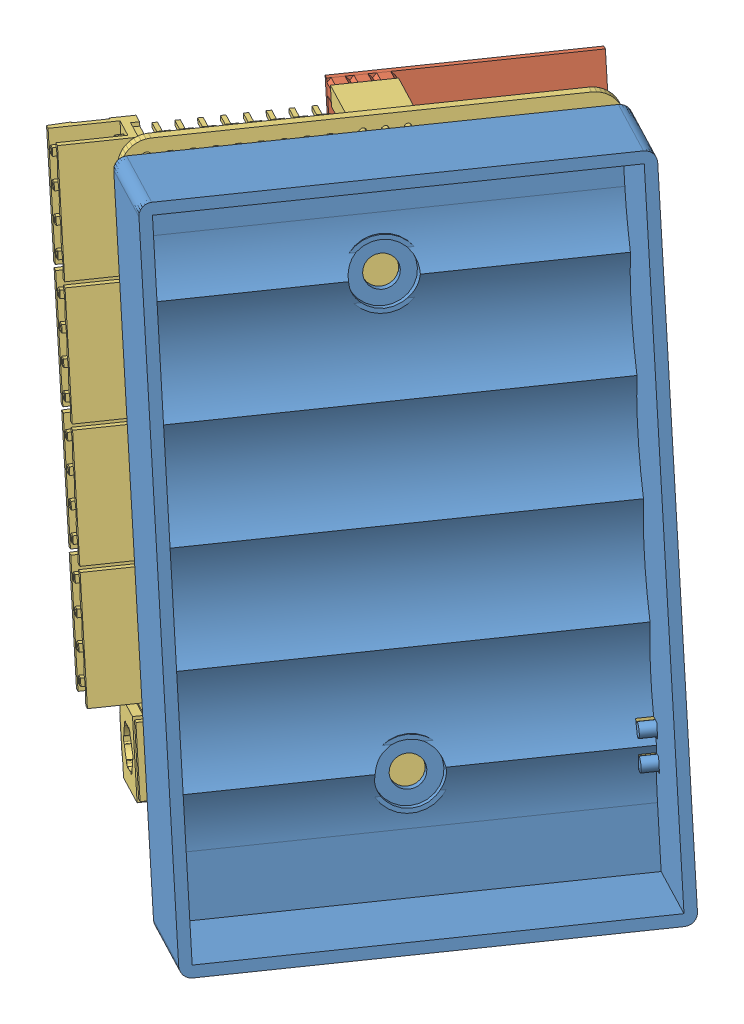
SolidWorks assembly Boitier_Electronique, configuration Défaut. Lengths in mm.
Overall size (84.35 91.62 83.87).
3 component instances, 3 part files, 7 mates.
Components (placement in the parent):
- Coupleur6PilesAA-1: Coupleur6PilesAA [Défaut] at (28.5112 -11.4596 149.0979) x (0.569655 -0.000137 -0.821884) z (-0.230919 0.959692 -0.160212) size (59.2 16.1 90)
- Bluetooth Module For mBot V1.0-1: Bluetooth Module For mBot V1.0 [Défaut] at (-5.2612 11.173 119.3562) x (-0.569622 0 0.821907) z (-0.788777 -0.281054 -0.546662) size (31 20.32 11.44)
- MegaPi-1: MegaPi [Défaut] at (4.2784 -56.3504 165.4648) x (-0.231 0.959692 -0.160095) z (-0.788777 -0.281054 -0.546662) size (85.5 62.93 15.25)
Mates (geometry in assembly coordinates):
- Coïncidente1: coincident: plane of Bluetooth Module For mBot V1.0-1 through (-3.7848 22.3366 126.7427) normal (-0.231 0.959692 -0.160095); line of MegaPi-1 through (-7.8645 20.9032 124.0369) axis (-0.569622 0 0.821907)
- Parallèle1: parallel anti-aligned: plane of Bluetooth Module For mBot V1.0-1 through (-5.1034 11.2292 119.4655) normal (0.788777 0.281054 0.546662); plane of MegaPi-1 through (-8.3435 20.5227 124.009) normal (-0.788777 -0.281054 -0.546662)
- Coïncidente6: coincident: plane of Bluetooth Module For mBot V1.0-1 through (-3.988 21.7607 127.3319) normal (-0.569622 0 0.821907); line of MegaPi-1 through (-8.1493 20.9032 124.4478) axis (0.231 -0.959692 0.160095)
- Coïncidente3: coincident anti-aligned: plane of Bluetooth Module For mBot V1.0-1 through (-8.3035 20.4748 123.9759) normal (0.788777 0.281054 0.546662); plane of MegaPi-1 through (-8.3435 20.5227 124.009) normal (-0.788777 -0.281054 -0.546662)
- Distance3: distance = 5 mm: plane of Coupleur6PilesAA-1 through (15.8119 -15.9845 140.2966) normal (-0.788777 -0.281054 -0.546662); plane of MegaPi-1 through (7.6553 -55.9734 163.4786) normal (0.788777 0.281054 0.546662)
- Coïncidente15: coincident: plane of Coupleur6PilesAA-1 through (42.6378 -59.1746 123.7948) normal (0.569655 -0.000137 -0.821884); plane of MegaPi-1 through (36.7541 -52.5182 119.7157) normal (0.569655 -0.000137 -0.821884)
- Coïncidente17: coincident: point of Coupleur6PilesAA-1; plane of MegaPi-1 through (15.8535 25.793 109.611) normal (-0.230871 0.959692 -0.160281)
